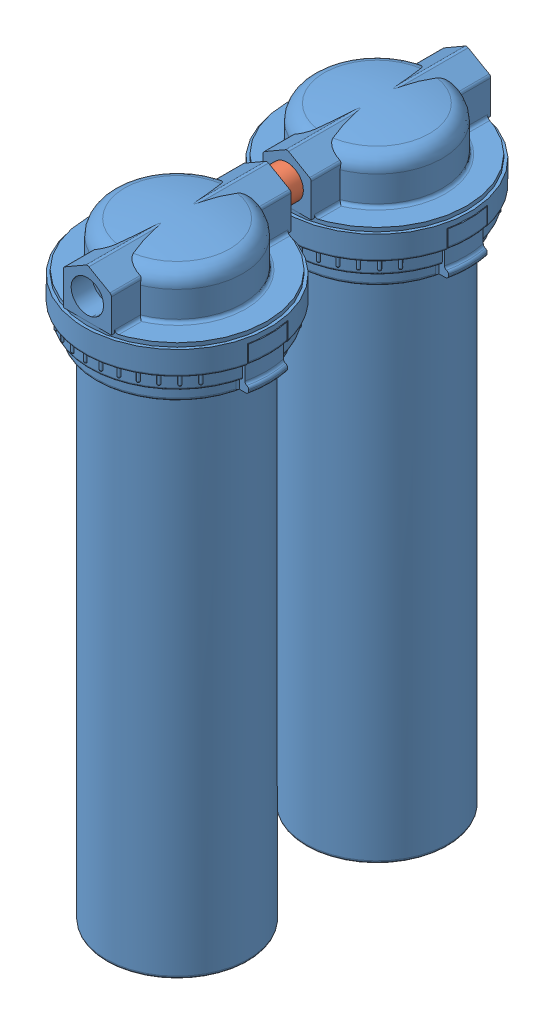
SolidWorks assembly ReadingTech_4P-150-M04-DC, configuration Default. Lengths in mm.
Overall size (121.86 425.94 252.73).
3 component instances, 2 part files, 3 mates.
Components (placement in the parent):
- ReadingTech_3P150M04F-1: ReadingTech_3P150M04F [Default] at (-26.7828 -163.7371 -3.6632) size (121.86 425.94 121.67)
- ReadingTech_3P150M04F-2: ReadingTech_3P150M04F [Default] at (-26.7828 -163.7371 -134.7272) size (121.86 425.94 121.67)
- ReadingTech- 90,150cfm_connector_.5in-1: ReadingTech- 90,150cfm_connector_.5in [Default] at (-26.7828 221.1999 -62.5912) x (1 0 0) z (0 1 0) size (21.34 13.21 21.34)
Mates (geometry in assembly coordinates):
- Coincident1: coincident anti-aligned: circle of ReadingTech_3P150M04F-2; circle of ReadingTech- 90,150cfm_connector_.5in-1
- Coincident2: coincident aligned: circle of ReadingTech_3P150M04F-1; circle of ReadingTech- 90,150cfm_connector_.5in-1
- Coincident3: coincident aligned: plane of ReadingTech_3P150M04F-1 through (-10.9713 229.9629 55.2648) normal (1 0 0); plane of ReadingTech_3P150M04F-2 through (-10.9713 229.9629 -75.7992) normal (1 0 0)
